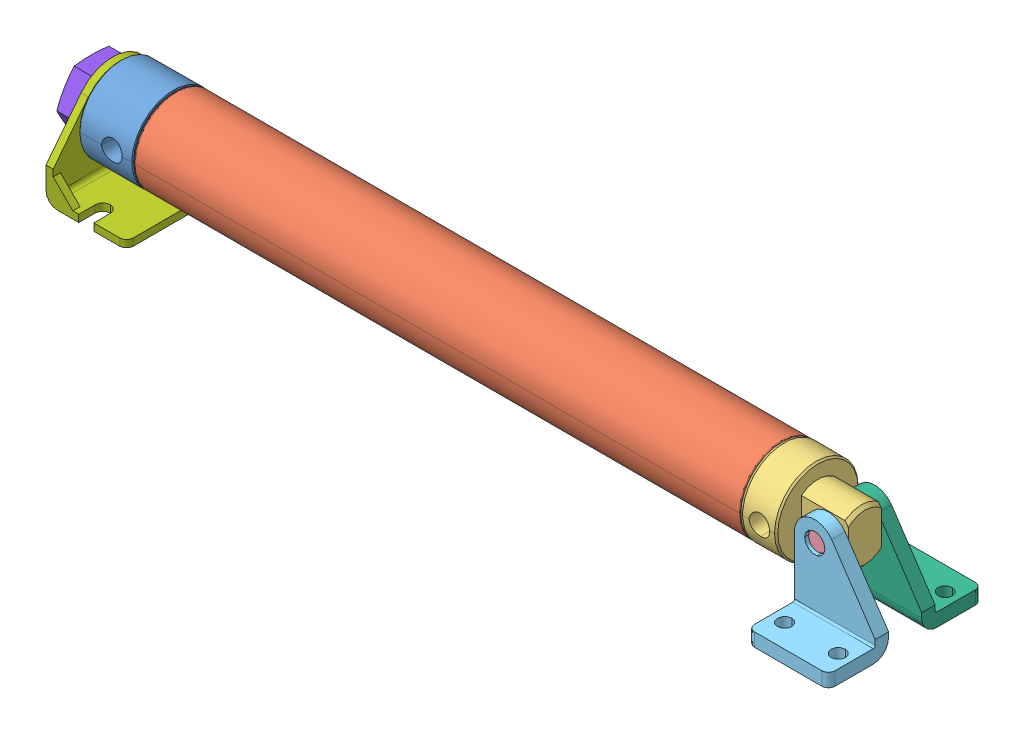
SolidWorks assembly 1710_DP_NOPISTON_WITHMOUNTS, configuration Default. Lengths in mm.
Overall size (387.48 58.32 72.57).
8 component instances, 8 part files, 12 mates.
Components (placement in the parent):
- _17R000_0_rod_guide_4-1: _17R000_0_rod_guide_4 [Default] at origin size (47.63 39.54 39.54)
- _17R_11_30250C_6-1: _17R_11_30250C_6 [Default] at (42.2275 0 0) size (288.92 39.54 39.54)
- _17P0000_rear_head_8-1: _17P0000_rear_head_8 [Default] at (323.977 0 0) size (44.45 39.54 39.61)
- _D_358_10-1: _D_358_10 [Default] at (358.902 0 0) x (1 0 0) z (0 0 -1) size (9.53 9.53 25.4)
- _D_14031_l_2-1: _D_14031_l_2 [Default] at (349.377 -34.925 7.8359) size (38.1 44.58 28.45)
- _D_14032_r_4-1: _D_14032_r_4 [Default] at (387.477 -34.925 -7.8359) x (-1 0 0) z (0 0 -1) size (38.1 44.58 28.45)
- D_241-1: D_241 [Default] at (12.4587 -25.4 31.623) x (0 0 -1) z (1 0 0) size (63.25 44.45 38.1)
- D_3556-1: D_3556 [Default] at (7.1247 0 0) x (1 0 0) z (0 0.5 0.866025) size (10.67 32.85 36.66)
Mates (geometry in assembly coordinates):
- Concentric4: concentric: cylinder of _17R000_0_rod_guide_4-1 through (15.875 0 0) axis (-1 0 0) radius 8.2995; cylinder of D_241-1 through (17.5831 0 0) axis (1 0 0) radius 9.6203
- Coincident8: coincident: plane of _17R000_0_rod_guide_4-1 through (15.875 0 0) normal (-1 0 0); plane of D_241-1 through (15.875 27.94 -31.623) normal (1 0 0)
- Concentric5: concentric: cylinder of _17R000_0_rod_guide_4-1 through (15.875 0 0) axis (-1 0 0) radius 9.525; cylinder of D_3556-1 through (12.4587 0 0) axis (-1 0 0) radius 8.6652
- Coincident10: coincident: plane of D_241-1 through (12.4587 -20.0025 -31.623) normal (-1 0 0); plane of D_3556-1 through (12.4587 8.2489 -4.7625) normal (1 0 0)
- Parallel4: parallel: plane of _17P0000_rear_head_8-1 through (346.202 39.5351 7.8359) normal (0 0 1); plane of D_241-1 through (17.8562 -20.0025 31.623) normal (0 0 1)
- Parallel5: parallel: plane of D_241-1 through (50.5587 -25.4 -31.623) normal (0 -1 0); plane of D_3556-1 through (17.7927 -14.224 8.2122) normal (0 -1 0)
- Concentric8: concentric: cylinder of _D_358_10-1 through (358.902 0 12.7) axis (0 0 -1) radius 4.7625; cylinder of _D_14032_r_4-1 through (358.902 0 -7.8359) axis (0 0 -1) radius 4.8006
- Coincident16: coincident: plane of _17P0000_rear_head_8-1 through (346.202 -39.5351 -7.8359) normal (0 0 -1); plane of _D_14032_r_4-1 through (349.377 -27.686 -7.8359) normal (0 0 1)
- Parallel7: parallel: plane of _17P0000_rear_head_8-1 through (346.202 19.0055 0) normal (1 0 0); plane of _D_14032_r_4-1 through (349.377 -27.686 -15.0749) normal (-1 0 0)
- Concentric9: concentric: cylinder of _D_14031_l_2-1 through (358.902 0 7.8359) axis (0 0 1) radius 4.8006; cylinder of _D_358_10-1 through (358.902 0 12.7) axis (0 0 -1) radius 4.7625
- Coincident18: coincident: plane of _17P0000_rear_head_8-1 through (346.202 39.5351 7.8359) normal (0 0 1); plane of _D_14031_l_2-1 through (387.477 -27.686 7.8359) normal (0 0 -1)
- Coincident20: coincident: plane of _D_14031_l_2-1 through (387.477 -34.925 36.2839) normal (0 -1 0); plane of _D_14032_r_4-1 through (349.377 -34.925 -36.2839) normal (0 -1 0)
